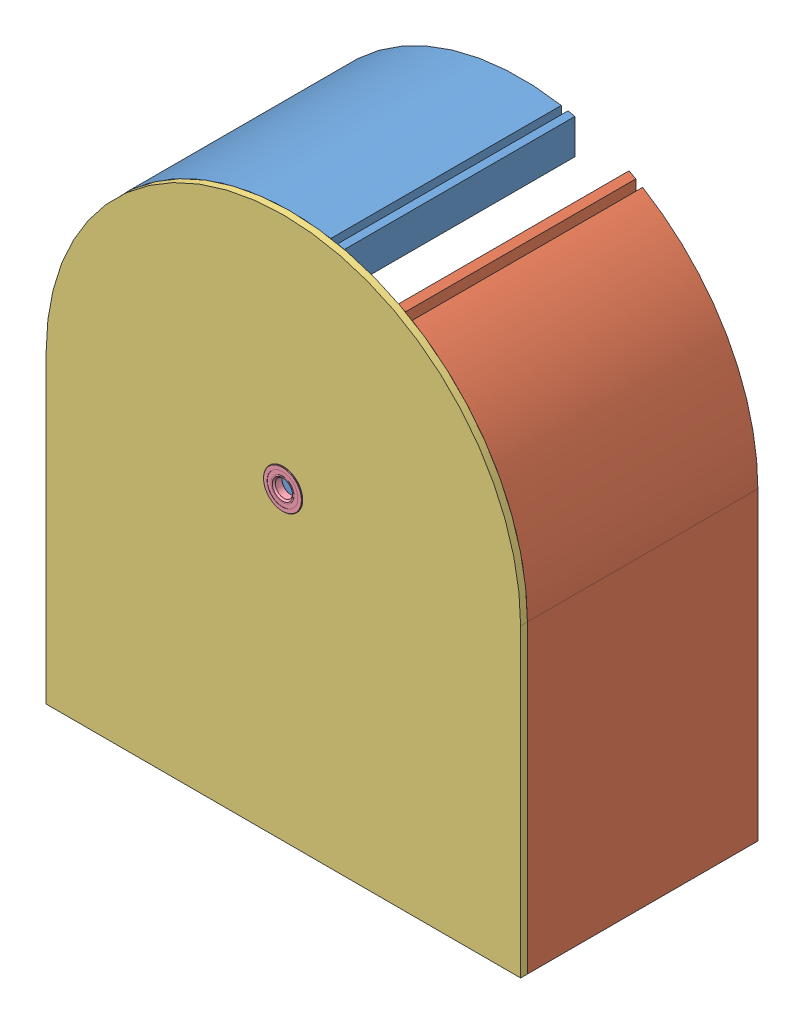
SolidWorks assembly 1.31 Upper Assembly, configuration Default. Lengths in mm.
Overall size (350 400 181.35).
7 component instances, 5 part files, 12 mates.
Components (placement in the parent):
- 1.29 outer casing-1: 1.29 outer casing [Default] at (80.7868 -0.4215 170.6253) size (350 400 5) (hidden)
- 1.31 Inner Ring Left Side-1: 1.31 Inner Ring Left Side [Default] at (80.7868 224.5785 175.6253) size (215 400 170)
- 1.31 Inner Ring Right Side-1: 1.31 Inner Ring Right Side [Default] at (80.7868 224.5785 175.6253) size (95 380.64 170)
- 1.29 outer casing-2: 1.29 outer casing [Default] at (80.7868 -0.4215 345.6253) size (350 400 5)
- 1.31 bearing 2342K166_PERMANENTLY LUBRICATED BALL BEARING-1: 1.31 bearing 2342K166_PERMANENTLY LUBRICATED BALL BEARING [2342K166] at (80.7868 224.5785 173.1253) x (0.6561 -0.754674 0) z (0 0 1) size (28.57 28.57 6.35)
- 1.31 bearing 2342K166_PERMANENTLY LUBRICATED BALL BEARING-2: 1.31 bearing 2342K166_PERMANENTLY LUBRICATED BALL BEARING [2342K166] at (80.7868 224.5785 348.1253) size (28.57 28.57 6.35)
- 2.1 flat mesh-1: 2.1 flat mesh [Default] at (-19.2132 74.5785 345.6253) x (1 0 0) z (0 0 -1) size (230 18.06 170)
Mates (geometry in assembly coordinates):
- Coincident1: coincident anti-aligned: plane of 1.29 outer casing-1 through (80.7868 224.5785 175.6253) normal (0 0 1); plane of 1.31 Inner Ring Left Side-1 through (80.7868 224.5785 175.6253) normal (0 0 -1)
- Coincident3: coincident aligned: circle of 1.29 outer casing-1; circle of 1.31 Inner Ring Left Side-1
- Coincident5: coincident aligned: circle of 1.29 outer casing-1; circle of 1.31 Inner Ring Right Side-1
- Coincident6: coincident aligned: circle of 1.31 Inner Ring Right Side-1; circle of 1.29 outer casing-2
- ProfileCenter1: profile center aligned: circle of 1.31 bearing 2342K166_PERMANENTLY LUBRICATED BALL BEARING-1; circle of 1.29 outer casing-1
- ProfileCenter2: profile center aligned: circle of 1.31 bearing 2342K166_PERMANENTLY LUBRICATED BALL BEARING-2; circle of 1.29 outer casing-2
- Coincident12: coincident: plane of 1.29 outer casing-1 through (80.7868 224.5785 175.6253) normal (0 0 1); plane of 2.1 flat mesh-1 through (-19.2132 65.24 175.6253) normal (0 0 -1)
- Coincident13: coincident aligned: line of 1.29 outer casing-1 through (-94.2132 -0.4215 175.6253) axis (1 0 0); line of 1.31 Inner Ring Left Side-1 through (-94.2132 -0.4215 175.6253) axis (1 0 0)
- Coincident14: coincident aligned: line of 1.29 outer casing-1 through (-94.2132 -0.4215 175.6253) axis (1 0 0); line of 1.31 Inner Ring Right Side-1 through (180.7868 -0.4215 175.6253) axis (1 0 0)
- Coincident15: coincident aligned: line of 1.31 Inner Ring Left Side-1 through (-94.2132 -0.4215 345.6253) axis (1 0 0); line of 1.29 outer casing-2 through (-94.2132 -0.4215 345.6253) axis (1 0 0)
- Coincident16: coincident: plane of 1.31 Inner Ring Left Side-1 through (-34.2132 63.0471 345.6253) normal (1 0 0); plane of 2.1 flat mesh-1 through (-34.2132 66.7715 345.6253) normal (-1 0 0)
- Coincident18: coincident anti-aligned: plane of 1.31 Inner Ring Left Side-1 through (-30.9226 78.4816 345.6253) normal (-0.316228 -0.948683 0); plane of 2.1 flat mesh-1 through (-19.2132 74.5785 345.6253) normal (0.316228 0.948683 0)
